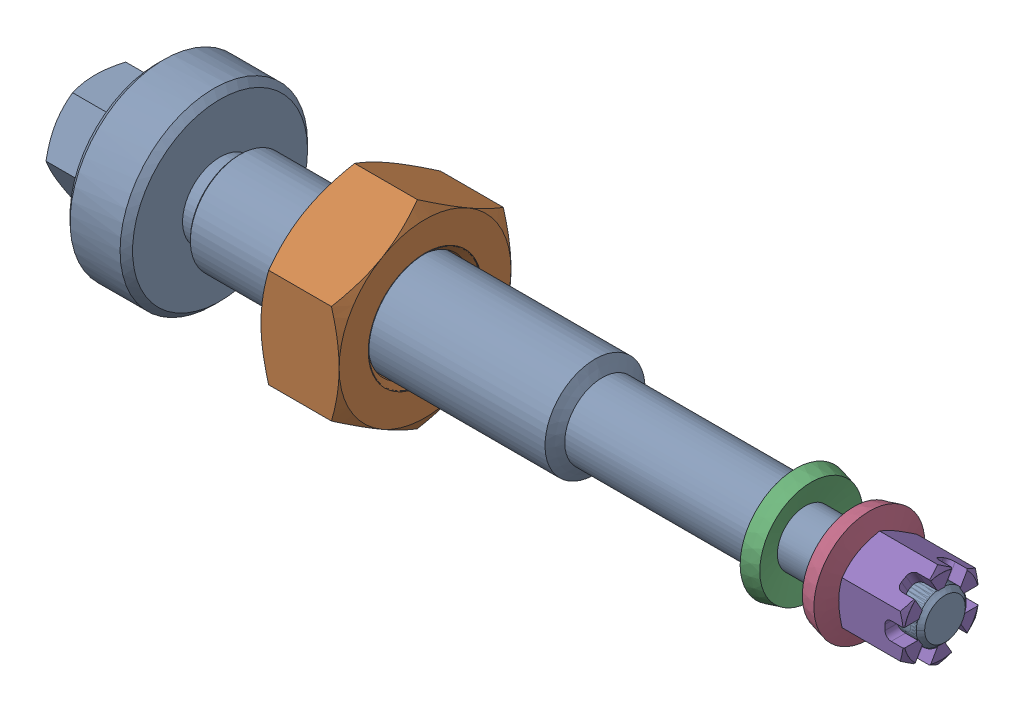
SolidWorks assembly g1_3_1_1_7_1, configuration 默认. Lengths in mm.
Overall size (272.02 63.51 60).
5 component instances, 4 part files, 0 mates.
Components (placement in the parent):
- g1_3_1_1_7-1_1-1: g1_3_1_1_7-1_1 [默认] at origin size (272.02 60 60)
- g1_3_1_1_7-2_1-1: g1_3_1_1_7-2_1 [默认] at (-104.3833 -31.7543 0) x (0 1 0) z (1 0 0) size (63.51 55 25)
- a35_5_gb1972_1-1: a35_5_gb1972_1 [默认] at (39.2167 0 0) x (0 0.075145 0.997173) z (0 0.997173 -0.075145) size (35.5 7.2 35.5)
- a35_5_gb1972_1-2: a35_5_gb1972_1 [默认] at (62.8167 0 0) x (0 -0.99777 0.066751) z (0 -0.066751 -0.99777) size (35.5 7.2 35.5)
- m16a_gb6178_1-1: m16a_gb6178_1 [默认] at (85.8167 13.8564 0) x (0 -1 0) z (-1 0 0) size (27.71 24 20.8)
